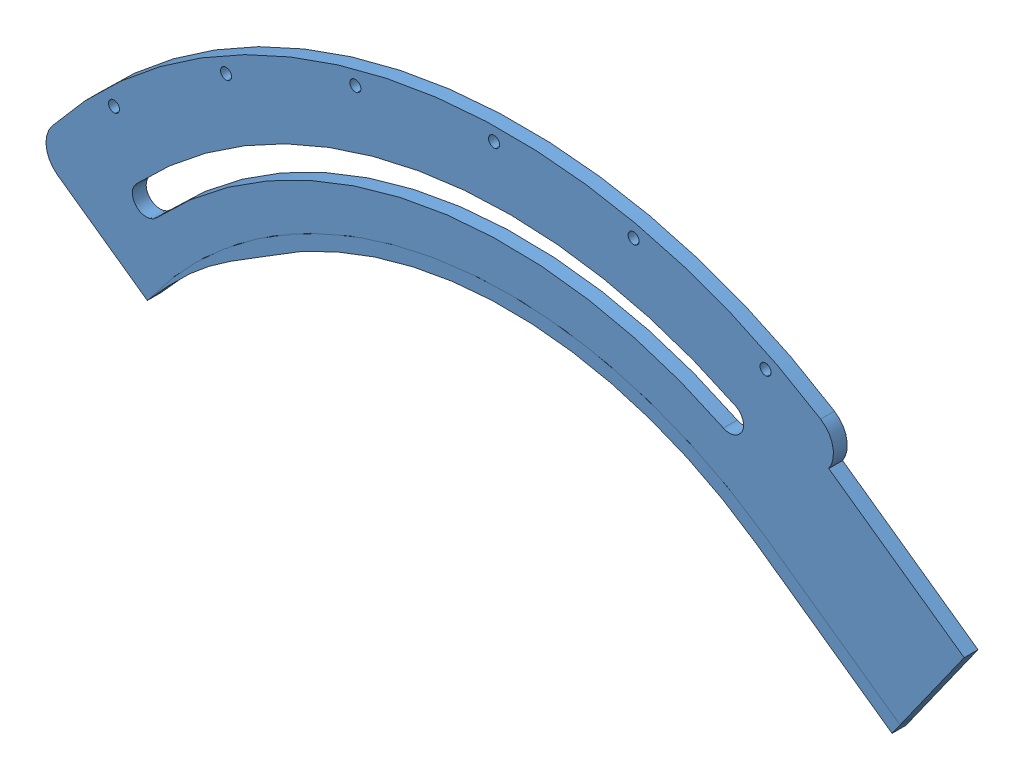
SolidWorks assembly CAM_Assem2, configuration Default. Lengths in mm.
Overall size (433.54 415.5 6.35).
4 component instances, 4 part files, 7 mates.
Components (placement in the parent):
- Table^CAM_Assem2-1: Table^CAM_Assem2 [Default] at (-1673.8784 81.0862 0) x (-1 0 0) z (0 0 1) size (508 1016 76.2) (hidden, virtual)
- Stock^CAM_Assem2-1: Stock^CAM_Assem2 [Default] at (-31.8259 -259.4983 9.525) x (1 0 0) z (0 1 0) size (482.6 6.35 406.4) (hidden, virtual)
- Side_Plate-2: Side_Plate [Default] at (-90.7538 -481.8965 9.525) x (0.815554 -0.578681 0) z (0 0 -1) size (342.58 266.38 6.35)
- Part2^CAM_Assem2-1: Part2^CAM_Assem2 [Default] at (-31.8259 -259.4983 9.525) x (-1 0 0) z (0 0 1) size (421.37 152.84 0) (virtual)
Mates (geometry in assembly coordinates):
- Coincident2: coincident aligned: plane of Side_Plate-2 through (-90.7538 -481.8965 9.525) normal (0 0 1); plane of Stock^CAM_Assem2-1 through (-31.8259 -259.4983 9.525) normal (0 0 1)
- Width2: width anti-aligned: plane of Stock^CAM_Assem2-1 through (-333.8868 -138.7665 3.175) normal (-1 0 0); plane of Stock^CAM_Assem2-1 through (148.7132 -138.7665 3.175) normal (1 0 0); plane of Table^CAM_Assem2-1 through (161.4132 382.3597 -76.2) normal (1 0 0); plane of Table^CAM_Assem2-1 through (-346.5868 382.3597 -76.2) normal (-1 0 0)
- Distance1: distance = 3.175 mm anti-aligned: plane of Stock^CAM_Assem2-1 through (-31.8259 -259.4983 3.175) normal (0 0 -1); plane of Table^CAM_Assem2-1 through (-1673.8784 81.0862 0) normal (0 0 1)
- InPlace2: in place: plane of Stock^CAM_Assem2-1 through (-31.8259 -259.4983 9.525) normal (0 0 1); plane of ? through (0 0 9.525) normal (0 0 1); moOrthogonalPlaneRef_w of Stock^CAM_Assem2-1 through (-31.8259 -259.4983 9.525) normal (0 0 1); plane of ? through (0 0 9.525) normal (0 1 0); plane of Stock^CAM_Assem2-1 through (-31.8259 -259.4983 9.525) normal (0 0 1); plane of ? through (0 0 9.525) normal (1 0 0); plane of Stock^CAM_Assem2-1 through (-31.8259 -259.4983 9.525) normal (0 0 1); unknown of Part2^CAM_Assem2-1
- Coincident7: coincident aligned: plane of Stock^CAM_Assem2-1; plane of Part2^CAM_Assem2-1
- Coincident8: coincident aligned: moOrthogonalPlaneRef_w of Stock^CAM_Assem2-1 through (-31.8259 -259.4983 9.525) normal (0 -1 0); plane of Part2^CAM_Assem2-1
- Coincident9: coincident anti-aligned: moOrthogonalPlaneRef_w of Stock^CAM_Assem2-1 through (-31.8259 -259.4983 9.525) normal (1 0 0); plane of Part2^CAM_Assem2-1
